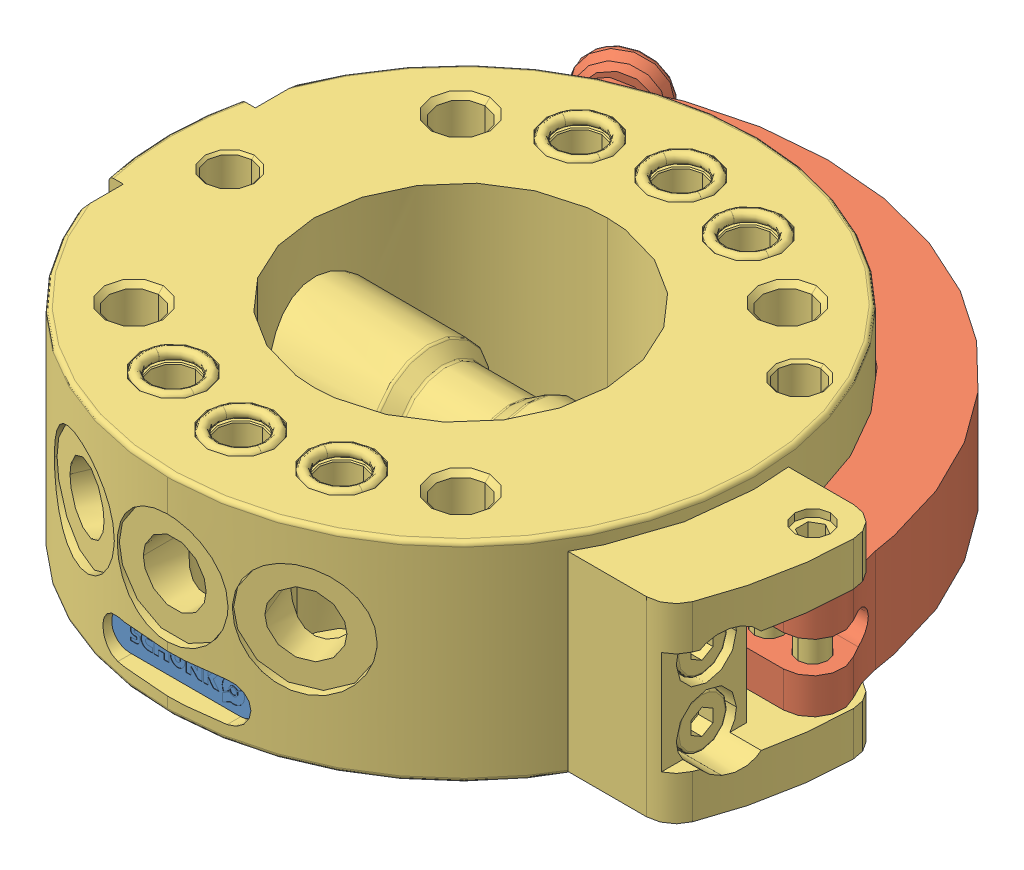
SolidWorks assembly SCHUNK_0310420_SHK_063_000_000_0000ohne, configuration Default. Lengths in mm.
Overall size (92.63 36.89 94.12).
3 component instances, 3 part files, 0 mates.
Components (placement in the parent):
- SCHUNK_0310420_SHK_063_000_000_0000ohne_3-1: SCHUNK_0310420_SHK_063_000_000_0000ohne_3 [Default] at (0 4.7 37.3) size (20 5 0.3)
- SCHUNK_0310420_SHK_063_000_000_0000ohne_5-1: SCHUNK_0310420_SHK_063_000_000_0000ohne_5 [Default] at (0 13.4 0) x (0 0 1) z (-1 0 0) size (58.11 14 86.81)
- SCHUNK_0310420_SHK_063_000_000_0000ohne_7-1: SCHUNK_0310420_SHK_063_000_000_0000ohne_7 [Default] x (-1 0 0) z (0 0 -1) size (92.63 36.89 80.01)
